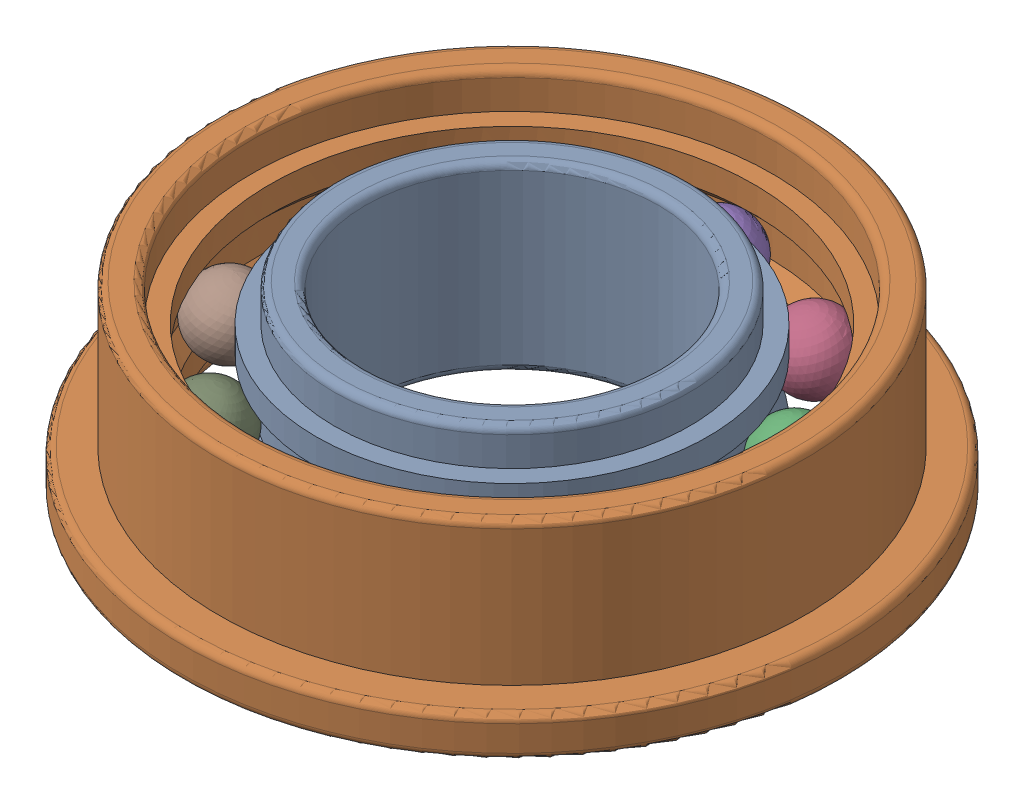
SolidWorks assembly V8_F688ZZ_assemblyURC 2024, configuration Default. Lengths in mm.
Overall size (20.89 5 20.89).
12 component instances, 3 part files, 8 mates.
Components (placement in the parent):
- V8_F688ZZ_shaftURC 2024-1: V8_F688ZZ_shaftURC 2024 [Default] at origin size (10.7 5 10.7)
- V8_F688ZZ_HousingURC 2024-1: V8_F688ZZ_HousingURC 2024 [Default] x (0.984312 0 0.176438) z (-0.176438 0 0.984312) size (18 5 18)
- V8_F688ZZ_BallURC 2024-1: V8_F688ZZ_BallURC 2024 [Default] at (5.5752 2.5 -2.1489) x (0.959238 0.232099 0.161224) z (-0.142462 -0.095558 0.985177) size (2 2 2)
- V8_F688ZZ_BallURC 2024-20: V8_F688ZZ_BallURC 2024 [Default] at (3.2474 2.5 -5.0155) x (0.870805 0.232099 -0.433393) z (0.463818 -0.095558 0.880762) size (2 2 2)
- V8_F688ZZ_BallURC 2024-21: V8_F688ZZ_BallURC 2024 [Default] at (-0.3209 2.5 -5.9664) x (0.449753 0.232099 -0.862469) z (0.892936 -0.095558 0.439926) size (2 2 2)
- V8_F688ZZ_BallURC 2024-22: V8_F688ZZ_BallURC 2024 [Default] at (-3.7665 2.5 -4.6383) x (-0.143088 0.232099 -0.96211) z (0.980982 -0.095558 -0.168947) size (2 2 2)
- V8_F688ZZ_BallURC 2024-23: V8_F688ZZ_BallURC 2024 [Default] at (-5.7735 2.5 -1.5385) x (-0.681275 0.232099 -0.694258) z (0.694326 -0.095558 -0.713288) size (2 2 2)
- V8_F688ZZ_BallURC 2024-24: V8_F688ZZ_BallURC 2024 [Default] at (-5.5752 2.5 2.1489) x (-0.959238 0.232099 -0.161224) z (0.142462 -0.095558 -0.985177) size (2 2 2)
- V8_F688ZZ_BallURC 2024-25: V8_F688ZZ_BallURC 2024 [Default] at (-3.2474 2.5 5.0155) x (-0.870805 0.232099 0.433393) z (-0.463818 -0.095558 -0.880762) size (2 2 2)
- V8_F688ZZ_BallURC 2024-26: V8_F688ZZ_BallURC 2024 [Default] at (0.3209 2.5 5.9664) x (-0.449753 0.232099 0.862469) z (-0.892936 -0.095558 -0.439926) size (2 2 2)
- V8_F688ZZ_BallURC 2024-27: V8_F688ZZ_BallURC 2024 [Default] at (3.7665 2.5 4.6383) x (0.143088 0.232099 0.96211) z (-0.980982 -0.095558 0.168947) size (2 2 2)
- V8_F688ZZ_BallURC 2024-28: V8_F688ZZ_BallURC 2024 [Default] at (5.7735 2.5 1.5385) x (0.681275 0.232099 0.694258) z (-0.694326 -0.095558 0.713288) size (2 2 2)
Mates (geometry in assembly coordinates):
- Eş Merkezli1: concentric aligned: cylinder of F688ZZ_shaft-1 through (0 5 0) axis (0 -1 0) radius 5.35; cylinder of F688ZZ_Housing-1 through (0 5 0) axis (0 -1 0) radius 6.6
- Çakışık2: coincident aligned: plane of F688ZZ_shaft-1 through (0 0 0) normal (0 -1 0); plane of F688ZZ_Housing-1 through (0 0 0) normal (0 -1 0)
- Teğet1: tangent anti-aligned: cylinder of F688ZZ_shaft-1 through (0 0 0) axis (0 -1 0) radius 4.975; sphere of F688ZZ_Ball-1
- Teğet2: tangent anti-aligned: cone of F688ZZ_shaft-1 through (0 1.5 0) axis (0 1 0); sphere of F688ZZ_Ball-1
- Teğet3: tangent anti-aligned: cone of F688ZZ_shaft-1 through (0 2.9142 0) axis (0 -1 0); sphere of F688ZZ_Ball-1
- Teğet4: tangent aligned: cylinder of F688ZZ_Housing-1 through (0 0 0) axis (0 -1 0) radius 6.975; sphere of F688ZZ_Ball-1
- Teğet5: tangent aligned: cone of F688ZZ_Housing-1 through (0 2.0858 0) axis (0 -1 0); sphere of F688ZZ_Ball-1
- Teğet6: tangent aligned: cone of F688ZZ_Housing-1 through (0 4 0) axis (0 1 0); sphere of F688ZZ_Ball-1
